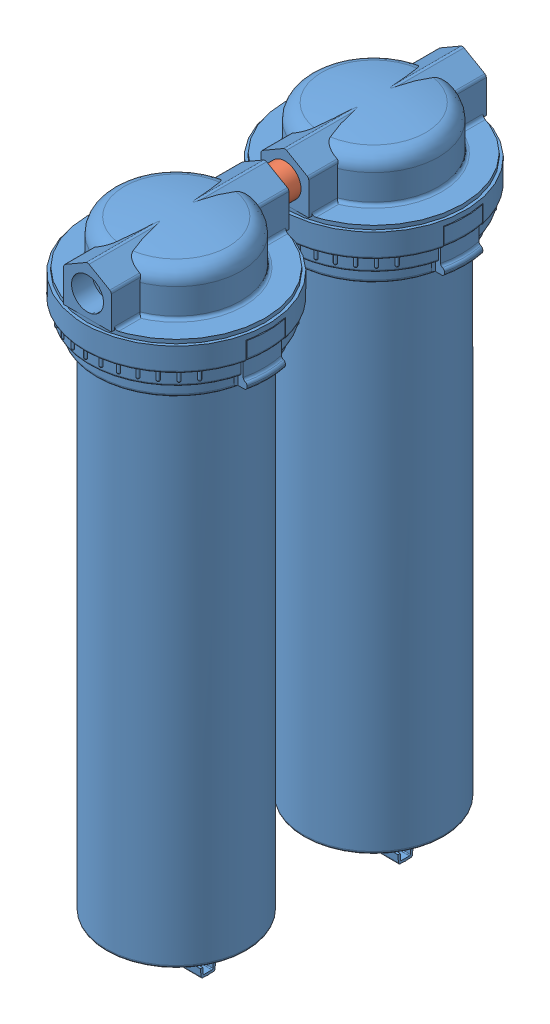
SolidWorks assembly ReadingTech_3P-150-M04-DCP, configuration Default. Lengths in mm.
Overall size (121.86 429.24 252.73).
3 component instances, 2 part files, 3 mates.
Components (placement in the parent):
- ReadingTech_3P-150-M04-P-1: ReadingTech_3P-150-M04-P [Default] at (16.9832 -175.404 -17.71) size (121.86 429.24 121.67)
- ReadingTech_3P-150-M04-P-2: ReadingTech_3P-150-M04-P [Default] at (16.9832 -175.404 -148.774) size (121.86 429.24 121.67)
- ReadingTech- 90,150cfm_connector_.5in-1: ReadingTech- 90,150cfm_connector_.5in [Default] at (16.9832 209.533 -76.638) x (1 0 0) z (0 1 0) size (21.34 13.21 21.34)
Mates (geometry in assembly coordinates):
- Coincident1: coincident anti-aligned: circle of ReadingTech_3P-150-M04-P-2; circle of ReadingTech- 90,150cfm_connector_.5in-1
- Coincident2: coincident aligned: circle of ReadingTech_3P-150-M04-P-1; circle of ReadingTech- 90,150cfm_connector_.5in-1
- Coincident3: coincident aligned: plane of ReadingTech_3P-150-M04-P-1 through (32.7947 218.296 41.218) normal (1 0 0); plane of ReadingTech_3P-150-M04-P-2 through (32.7947 218.296 -89.846) normal (1 0 0)
